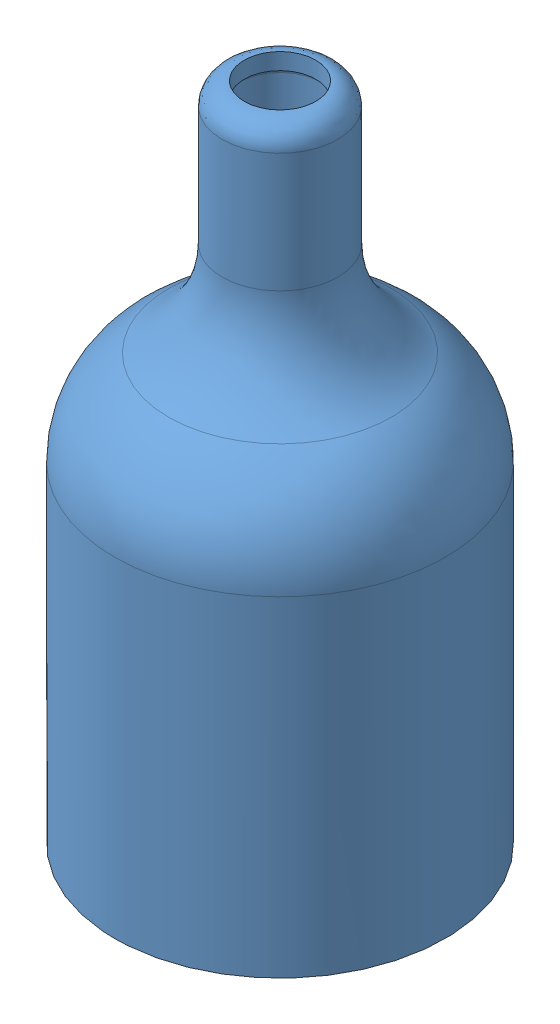
SolidWorks assembly Bottle_with_disc, configuration Default. Lengths in mm.
Overall size (30 60 30).
2 component instances, 2 part files, 1 mates.
Components (placement in the parent):
- Bottle-1: Bottle [Default] at (46.6954 -0.9962 34.8005) size (30 60 30)
- Disc-1: Disc [Default] at (46.6954 8.9182 34.8005) x (0.999368 0 0.035551) z (-0.035551 0 0.999368) size (25 1 25)
Mates (geometry in assembly coordinates):
- Concentric1: concentric aligned: circle of Bottle-1; circle of Disc-1
